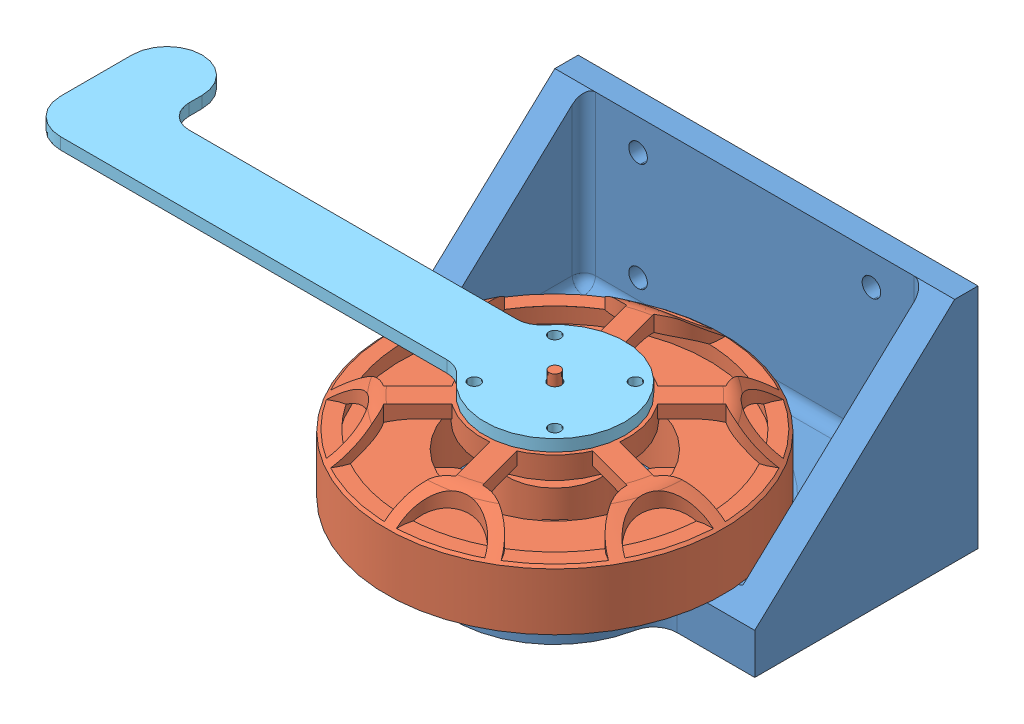
SolidWorks assembly Torque Tester, configuration Default. Lengths in mm.
Overall size (199.34 61.91 129.63).
5 component instances, 5 part files, 8 mates.
Components (placement in the parent):
- MotorMountTorque Tester-1: MotorMountTorque Tester [Default] at origin size (108.81 61.91 88.25)
- 9225 160kv-1: 9225 160kv [Default] at (0 -3.93 0) x (0.707107 0 0.707107) z (-0.707107 0 0.707107) size (91.66 44.53 91.66)
- Magnut hex puck-1: Magnut hex puck [Default] at (0 -3.93 0) size (22.94 6.48 22.94)
- AS5047D Dev Board-1: AS5047D Dev Board [Default] at (0 -11.1125 0) x (0 0 1) z (-1 0 0) size (22 6.88 28.22)
- Part8^Torque Tester-1: Part8^Torque Tester [Default] at origin size (153.58 3.18 48.05) (virtual)
Mates (geometry in assembly coordinates):
- Coincident5: coincident: point of 9225 160kv-1; point of Magnut hex puck-1
- Coincident2: coincident aligned: line of 9225 160kv-1 through (41.998 0 36.159) axis (0 0 -1)
- Parallel1: parallel anti-aligned: plane of MotorMountTorque Tester-1 through (-3.25 -3.175 -37.5487) normal (0 0 1); plane of 9225 160kv-1 through (-3.25 -10.28 -36.33) normal (0 0 -1)
- Coincident4: coincident anti-aligned: plane of MotorMountTorque Tester-1 through (0 0 0) normal (0 1 0); plane of 9225 160kv-1 through (6.8236 0 6.8236) normal (0 -1 0)
- Coincident6: coincident: unknown of AS5047D Dev Board-1
- Parallel2: parallel anti-aligned: plane of AS5047D Dev Board-1 through (0 -11.1125 0) normal (0 -1 0)
- Parallel3: parallel: line of AS5047D Dev Board-1 through (20.6542 -11.1125 11) axis (0 0 -1)
- Coincident9: coincident aligned: plane of MotorMountTorque Tester-1 through (33.2491 -11.1125 6.35) normal (0 -1 0); plane of AS5047D Dev Board-1 through (0 -11.1125 0) normal (0 -1 0)
